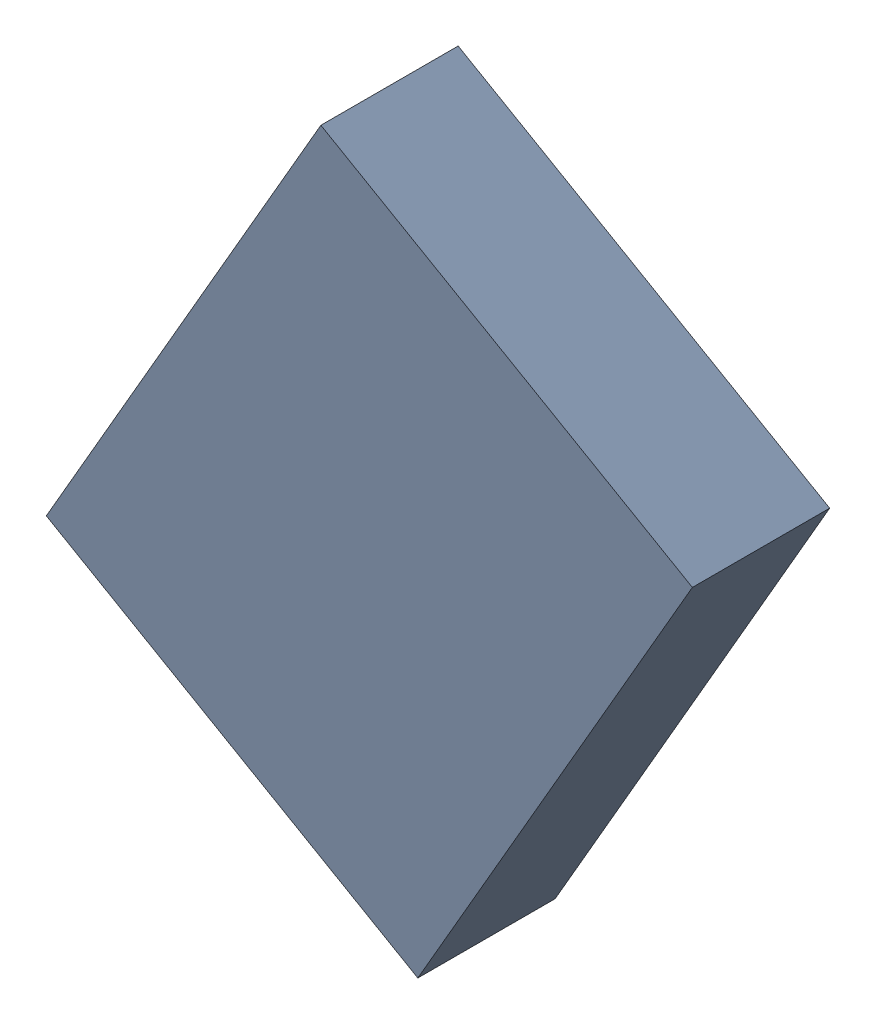
SolidWorks assembly X_TDA_TDA6, configuration Standard. Lengths in mm.
Overall size (3.77 4.02 0.8).
2 component instances, 1 part files, 0 mates.
Components (placement in the parent):
- 885545368-1: 885545368 [Standard] at (-35.3942 22.6879 0) size (3.77 4.02 0.8)
  - Extruded-1: Extruded [Standard] at origin size (3.77 4.02 0.8)
